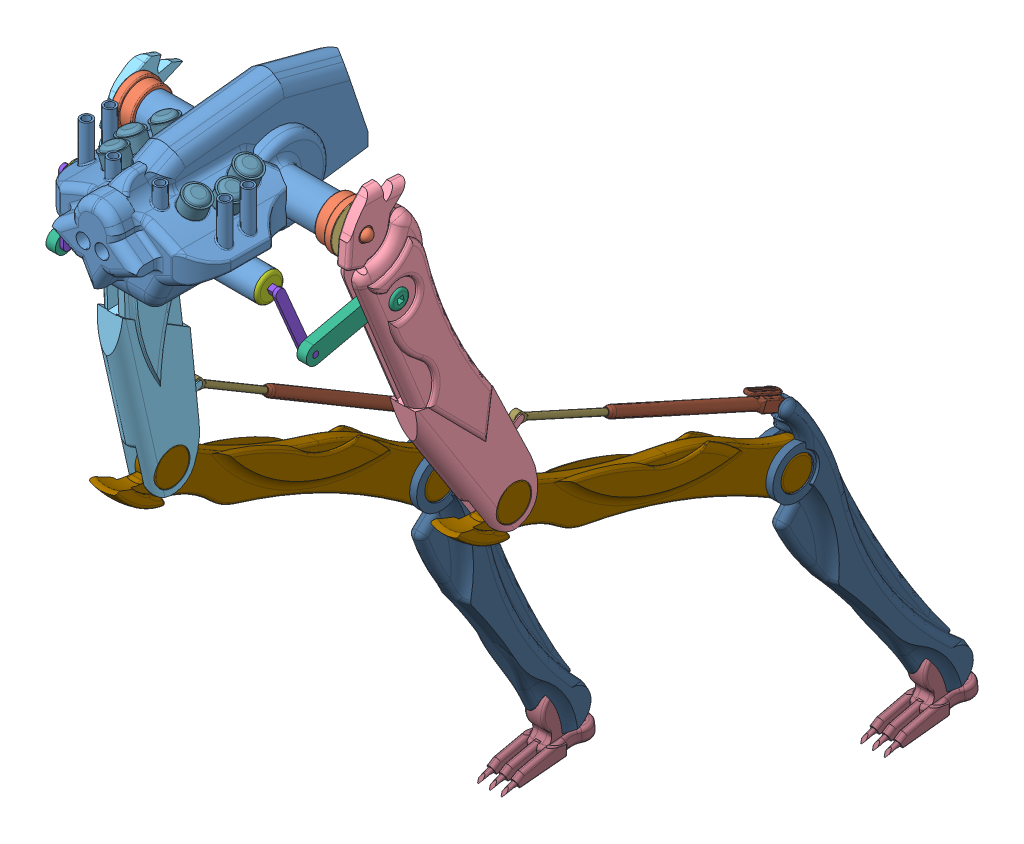
SolidWorks assembly canine rear end assembly, configuration Default. Lengths in mm.
Overall size (300.66 924.94 830.6).
29 component instances, 14 part files, 50 mates.
Components (placement in the parent):
- hind quarters-1: hind quarters [Default] at origin size (223.52 141.12 290.2)
- rear brushless hub motor-1: rear brushless hub motor [Default] at (99.06 -5.0738 -138.7243) x (1 0 0) z (0 -0.469696 0.882828) size (39.37 50.8 50.8)
- rear brushless hub motor cap-1: rear brushless hub motor cap [Default] at (119.38 -5.0738 -138.7243) x (1 0 0) z (0 0.469696 -0.882828) size (2.92 50.8 50.8)
- rear brushless hub motor cap-2: rear brushless hub motor cap [Default] at (-119.38 -5.0738 -138.7243) x (-1 0 0) z (0 0.843068 -0.537807) size (2.92 50.8 50.8)
- rear brushless hub motor-2: rear brushless hub motor [Default] at (-99.06 -5.0738 -138.7243) x (-1 0 0) z (0 -0.843068 0.537807) size (39.37 50.8 50.8)
- upper rear left leg-1: upper rear left leg [Default] at (120.015 -5.0738 -138.7243) x (1 0 0) z (0 -0.537598 0.843201) size (35.47 408.3 128.58)
- upper rear right leg-1: upper rear right leg [Default] at (-94.615 -5.0738 -138.7243) x (1 0 0) z (0 -0.219511 0.97561) size (35.47 408.3 128.58)
- upper rear leg slider control bar-1: upper rear leg slider control bar [Default] at (122.936 -76.9118 -167.7908) x (1 0 0) z (0 -0.218138 0.975918) size (27.94 20.32 101.6)
- rear leg motion controller-1: rear leg motion controller [Default] at (78.74 -29.21 -60.599) x (1 0 0) z (0 -0.391862 0.920024) size (28.55 30.48 30.48)
- rear leg motion control rod-1: rear leg motion control rod [Default] at (114.808 -29.21 -60.599) x (1 0 0) z (0 0.920024 0.391862) size (26.67 10.16 81.28)
- rear leg motion controller-2: rear leg motion controller [Default] at (-78.74 -29.21 -60.599) x (-1 0 0) z (0 0.999688 0.024987) size (28.55 30.48 30.48)
- rear leg motion control rod-2: rear leg motion control rod [Default] at (-114.808 -29.21 -60.599) x (-1 0 0) z (0 0.999688 0.024987) size (26.67 10.16 81.28)
- upper rear leg slider control bar-2: upper rear leg slider control bar [Default] at (-122.936 -82.5128 -141.6841) x (-1 0 0) z (0 -0.218934 0.97574) size (27.94 20.32 101.6)
- middle rear leg-1: middle rear leg [Default] at (125.476 -329.7756 -292.0752) x (1 0 0) z (0 -0.925849 0.377893) size (41.3 413.23 74.4)
- middle rear leg-2: middle rear leg [Default] at (-125.476 -362.549 -172.7712) x (1 0 0) z (0 -0.877949 0.478754) size (41.3 413.23 74.4)
- lower rear leg-1: lower rear leg [Default] at (125.476 -454.5559 -597.7905) x (1 0 0) z (0 -0.509949 0.860205) size (49.71 405.22 76.89)
- lower rear leg-2: lower rear leg [Default] at (-125.476 -520.6335 -462.67) x (1 0 0) z (0 -0.419045 0.907965) size (49.71 405.22 76.89)
- lower rear leg motion sensor controller-1: lower rear leg motion sensor controller [Default] at (125.476 -392.2744 -591.0817) x (1 0 0) z (0 -0.910887 0.412655) size (20.32 209.55 18.41)
- lower rear leg motion sensor controller-2: lower rear leg motion sensor controller [Default] at (-125.476 -457.9923 -462.3835) x (1 0 0) z (0 -0.860333 0.509732) size (20.32 209.55 18.41)
- lower rear leg control rod-1: lower rear leg control rod [Default] at (125.476 -264.3916 -308.7955) x (1 0 0) z (0 0.412655 0.910887) size (6.74 11.43 217.51)
- lower rear leg control rod-2: lower rear leg control rod [Default] at (-125.476 -309.1988 -211.2475) x (1 0 0) z (0 0.509732 0.860333) size (6.74 11.43 217.51)
- rear claws-1: rear claws [Default] at (125.476 -721.5295 -764.2105) x (1 0 0) z (0 -0.108311 0.994117) size (34.48 64.13 105.72)
- rear claws-2: rear claws [Default] at (-125.476 -803.266 -600.8342) x (1 0 0) z (0 -0.091013 0.99585) size (34.48 64.13 105.72)
- fluids container-1: fluids container [Default] at (25.9582 -13.2367 -42.5839) x (0.929939 -0.367713 -0.000069) z (-0.000069 -0.000362 1) size (26.67 57.15 26.67)
- fluids container-2: fluids container [Default] at (35.4101 -16.9633 -70.5239) x (0.929939 -0.367713 -0.000069) z (-0.000069 -0.000362 1) size (26.67 57.15 26.67)
- fluids container-3: fluids container [Default] at (25.9656 -13.2179 -98.4639) x (0.929939 -0.367713 -0.000069) z (-0.000069 -0.000362 1) size (26.67 57.15 26.67)
- fluids container-4: fluids container [Default] at (-25.9656 -13.2179 -98.4639) x (0.929939 0.367713 0.000069) z (0.000069 -0.000362 1) size (26.67 57.15 26.67)
- fluids container-5: fluids container [Default] at (-35.4101 -16.9633 -70.5239) x (0.929939 0.367713 0.000069) z (0.000069 -0.000362 1) size (26.67 57.15 26.67)
- fluids container-6: fluids container [Default] at (-25.9582 -13.2367 -42.5839) x (0.929939 0.367713 0.000069) z (0.000069 -0.000362 1) size (26.67 57.15 26.67)
Mates (geometry in assembly coordinates):
- Coincident1: coordinate: point of hind quarters-1; point of assembly
- Coincident2: coincident aligned: circle of hind quarters-1; circle of rear brushless hub motor-1
- Coincident3: coincident anti-aligned: circle of rear brushless hub motor-1; circle of rear brushless hub motor cap-1
- Coincident4: coincident anti-aligned: cylinder of rear brushless hub motor-1 through (132.08 -5.0738 -138.7243) axis (-1 0 0) radius 7.62; circle of rear brushless hub motor cap-1
- Coincident5: coincident anti-aligned: circle of hind quarters-1; circle of rear brushless hub motor-2
- Coincident6: coincident anti-aligned: circle of rear brushless hub motor cap-2; circle of rear brushless hub motor-2
- Concentric1: concentric anti-aligned: circle of rear brushless hub motor cap-2; cylinder of rear brushless hub motor-2 through (-132.08 -5.0738 -138.7243) axis (1 0 0) radius 7.62
- Concentric3: concentric aligned: cylinder of rear brushless hub motor-1 through (132.08 -5.0738 -138.7243) axis (-1 0 0) radius 7.62; cylinder of upper rear left leg-1 through (132.207 -5.0738 -138.7243) axis (-1 0 0) radius 7.62
- Coincident8: coincident anti-aligned: plane of rear brushless hub motor cap-1 through (120.015 -5.0738 -138.7243) normal (1 0 0); plane of upper rear left leg-1 through (120.015 -5.0738 -138.7243) normal (-1 0 0)
- Concentric4: concentric aligned: cylinder of rear brushless hub motor-2 through (-132.08 -5.0738 -138.7243) axis (1 0 0) radius 7.62; cylinder of upper rear right leg-1 through (-132.207 -5.0738 -138.7243) axis (1 0 0) radius 7.62
- Coincident9: coincident anti-aligned: plane of rear brushless hub motor cap-2 through (-120.015 -5.0738 -138.7243) normal (-1 0 0); plane of upper rear right leg-1 through (-120.015 -5.0738 -138.7243) normal (1 0 0)
- Coincident10: coincident aligned: plane of upper rear left leg-1 through (112.776 -42.69 -156.2825) normal (-1 0 0); plane of upper rear leg slider control bar-1 through (112.776 -76.9118 -167.7908) normal (-1 0 0)
- Coincident11: coincident aligned: circle of hind quarters-1; circle of rear leg motion controller-1
- Concentric5: concentric anti-aligned: cylinder of upper rear leg slider control bar-1 through (112.776 -94.6421 -88.4682) axis (1 0 0) radius 3.175; cylinder of rear leg motion control rod-1 through (128.016 -94.6421 -88.4682) axis (-1 0 0) radius 3.175
- Concentric7: concentric aligned: cylinder of upper rear left leg-1 through (139.446 -76.9118 -167.7908) axis (-1 0 0) radius 10.16; cylinder of upper rear leg slider control bar-1 through (133.096 -76.9118 -167.7908) axis (-1 0 0) radius 10.16
- Coincident13: coincident anti-aligned: plane of rear leg motion controller-1 through (94.5896 -33.3752 -58.9221) normal (0 0.391862 -0.920024); plane of rear leg motion control rod-1 through (101.346 -27.5331 -56.4337) normal (0 -0.391862 0.920024)
- Coincident14: coincident anti-aligned: plane of rear leg motion controller-1 through (94.5896 -33.3752 -58.9221) normal (0 0.920024 0.391862); plane of rear leg motion control rod-1 through (101.346 -30.8869 -64.7642) normal (0 -0.920024 -0.391862)
- LimitAngle1: limit planar angle = 1.168142 rad aligned: plane of assembly through (0 0 0) normal (0 1 0); plane of rear leg motion control rod-1 through (114.046 -27.2193 -65.2727) normal (0 0.391862 -0.920024)
- Coincident15: coincident anti-aligned: circle of hind quarters-1; circle of rear leg motion controller-2
- Parallel1: parallel anti-aligned: plane of rear leg motion controller-2 through (-107.2896 -29.21 -60.599) normal (-1 0 0); plane of rear leg motion control rod-2 through (-114.046 -29.21 -60.599) normal (1 0 0)
- Coincident17: coincident anti-aligned: plane of rear leg motion controller-2 through (-94.5896 -26.1153 -57.3456) normal (0 0.024987 -0.999688); plane of rear leg motion control rod-2 through (-101.346 -26.1153 -57.3456) normal (0 -0.024987 0.999688)
- Coincident18: coincident anti-aligned: plane of rear leg motion controller-2 through (-94.5896 -32.3047 -63.8523) normal (0 0.999688 0.024987); plane of rear leg motion control rod-2 through (-101.346 -32.4633 -57.5043) normal (0 -0.999688 -0.024987)
- Coincident19: coincident aligned: circle of rear leg motion control rod-2; circle of upper rear leg slider control bar-2
- Coincident20: coincident anti-aligned: plane of upper rear right leg-1 through (-117.856 -54.3408 -263.8851) normal (-1 0 0); plane of upper rear leg slider control bar-2 through (-117.856 -100.3078 -62.376) normal (1 0 0)
- Concentric8: concentric aligned: cylinder of upper rear right leg-1 through (-139.446 -82.5128 -141.6841) axis (1 0 0) radius 10.16; cylinder of upper rear leg slider control bar-2 through (-133.096 -82.5128 -141.6841) axis (1 0 0) radius 10.16
- LimitAngle2: limit planar angle = 1.545807 rad aligned: plane of rear leg motion control rod-2 through (-114.046 -29.0831 -65.6774) normal (0 0.024987 -0.999688); plane of assembly through (0 0 0) normal (0 1 0)
- Concentric9: concentric anti-aligned: cylinder of upper rear left leg-1 through (75.184 -329.7756 -292.0752) axis (1 0 0) radius 19.05; cylinder of middle rear leg-1 through (139.446 -329.7756 -292.0752) axis (-1 0 0) radius 19.05
- Coincident21: coincident aligned: plane of upper rear left leg-1 through (139.446 -326.8559 -243.6706) normal (1 0 0); plane of middle rear leg-1 through (139.446 -329.7756 -292.0752) normal (1 0 0)
- Coincident22: coincident aligned: plane of upper rear right leg-1 through (-111.506 -343.3745 -128.2306) normal (1 0 0); plane of middle rear leg-2 through (-111.506 -362.549 -172.7712) normal (1 0 0)
- Concentric10: concentric anti-aligned: cylinder of upper rear right leg-1 through (-139.446 -362.549 -172.7712) axis (1 0 0) radius 19.05; cylinder of middle rear leg-2 through (-111.506 -362.549 -172.7712) axis (-1 0 0) radius 19.05
- Concentric11: concentric anti-aligned: cylinder of middle rear leg-1 through (110.236 -454.5559 -597.7905) axis (1 0 0) radius 17.78; cylinder of lower rear leg-1 through (140.716 -454.5559 -597.7905) axis (-1 0 0) radius 17.78
- Coincident23: coincident aligned: plane of middle rear leg-1 through (140.716 -454.5559 -597.7905) normal (1 0 0); plane of lower rear leg-1 through (140.716 -454.5559 -597.7905) normal (1 0 0)
- Concentric12: concentric anti-aligned: cylinder of middle rear leg-2 through (-140.716 -520.6335 -462.67) axis (1 0 0) radius 17.78; cylinder of lower rear leg-2 through (-110.236 -520.6335 -462.67) axis (-1 0 0) radius 17.78
- Coincident24: coincident aligned: plane of middle rear leg-2 through (-110.236 -520.6335 -462.67) normal (1 0 0); plane of lower rear leg-2 through (-110.236 -520.6335 -462.67) normal (1 0 0)
- LimitAngle3: limit planar angle = 0.648151 rad aligned: plane of middle rear leg-1 through (125.476 -329.7756 -292.0752) normal (0 -0.925849 0.377893); plane of lower rear leg-1 through (125.476 -454.5559 -597.7905) normal (0 -0.509949 0.860205)
- LimitAngle4: limit planar angle = 0.639168 rad aligned: plane of middle rear leg-2 through (-125.476 -362.549 -172.7712) normal (0 -0.877949 0.478754); plane of lower rear leg-2 through (-125.476 -520.6335 -462.67) normal (0 -0.419045 0.907965)
- LimitAngle5: limit planar angle = 0.615691 rad aligned: plane of upper rear left leg-1 through (120.015 -5.0738 -138.7243) normal (0 -0.537598 0.843201); plane of middle rear leg-1 through (125.476 -329.7756 -292.0752) normal (0 -0.925849 0.377893)
- LimitAngle6: limit planar angle = 0.850249 rad aligned: plane of upper rear right leg-1 through (-94.615 -5.0738 -138.7243) normal (0 -0.219511 0.97561); plane of middle rear leg-2 through (-125.476 -362.549 -172.7712) normal (0 -0.877949 0.478754)
- Coincident25: coincident aligned: circle of lower rear leg-1; circle of lower rear leg motion sensor controller-1
- Coincident26: coincident aligned: circle of lower rear leg-2; circle of lower rear leg motion sensor controller-2
- Concentric13: concentric anti-aligned: cylinder of lower rear leg motion sensor controller-1 through (125.476 -307.8988 -404.8325) axis (0 -0.412655 -0.910887) radius 5.715; cylinder of lower rear leg control rod-1 through (125.476 -351.7906 -501.7184) axis (0 0.412655 0.910887) radius 3.175
- Coincident27: coincident aligned: circle of upper rear right leg-1; circle of lower rear leg control rod-2
- Concentric15: concentric anti-aligned: cylinder of lower rear leg motion sensor controller-2 through (-125.476 -353.7674 -286.4712) axis (0 -0.509732 -0.860333) radius 5.715; cylinder of lower rear leg control rod-2 through (-125.476 -417.1583 -393.4633) axis (0 0.509732 0.860333) radius 3.175
- Coincident28: coincident anti-aligned: circle of upper rear left leg-1; circle of lower rear leg control rod-1
- Coincident29: coincident aligned: circle of lower rear leg-1; circle of rear claws-1
- Coincident30: coincident aligned: plane of upper rear leg slider control bar-1 through (128.016 -94.6421 -88.4682) normal (1 0 0); plane of rear leg motion control rod-1 through (128.016 -94.6421 -88.4682) normal (1 0 0)
- Coincident31: coincident anti-aligned: circle of lower rear leg-2; circle of rear claws-2
- Coincident32: coincident anti-aligned: circle of hind quarters-1; circle of fluids container-1
- Coincident33: coincident anti-aligned: circle of hind quarters-1; circle of fluids container-2
- Coincident34: coincident anti-aligned: circle of hind quarters-1; circle of fluids container-3
